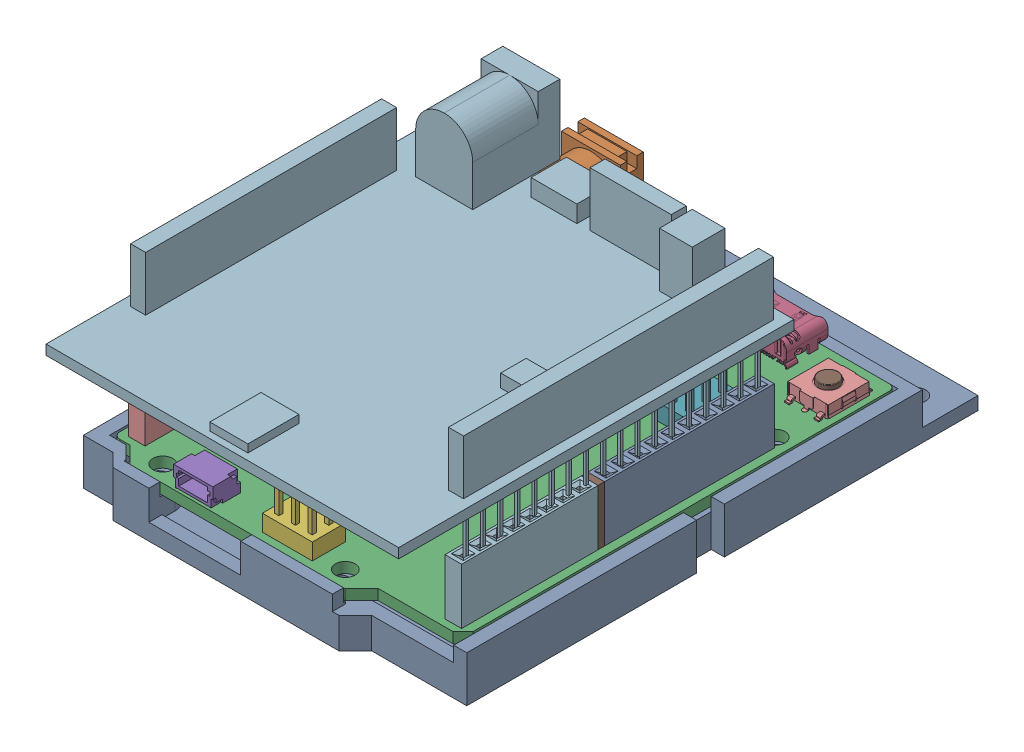
SolidWorks assembly Arduino_And_GPS_Module_C, configuration Default. Lengths in mm.
Overall size (59.4 35.6 86.3).
4 component instances, 3 part files, 4 mates.
Components (placement in the parent):
- Arduino_With_Mount_B-1: Arduino_With_Mount_B [Default] at origin size (59.4 17.89 80.5)
  - Arduino_Mount_B-2: Arduino_Mount_B [Default] at (0 2 0) x (-1 0 0) z (0 0 1) size (59.4 8 80.5)
  - Arduino_Uno_R4_Wifi_A-1: Arduino_Uno_R4_Wifi_A [Default] at (-26.67 7 -30.29) x (0 0 1) z (0 1 0) size (70.54 53.34 14.5)
- Pozyx-shield_A-1: Pozyx-shield_A [Default] at (0 22.5 15.6465) x (0 0 -1) z (1 0 0) size (63.6 25.6 53.8)
Mates (geometry in assembly coordinates):
- Parallel3: parallel anti-aligned: plane of Arduino_With_Mount_A-1/Arduino_Uno_R4_Wifi_A-1 through (-0.0974 7 3.3449) normal (0 1 0); plane of Pozyx-shield_A-1 through (0 22.5 15.6465) normal (0 -1 0)
- Width4: width anti-aligned: plane of Pozyx-shield_A-1 through (26.9 24 45.7965) normal (1 0 0); plane of Pozyx-shield_A-1 through (-26.9 24 45.7965) normal (-1 0 0); plane of Arduino_With_Mount_A-1/Arduino_Uno_R4_Wifi_A-1 through (-26.67 5.3937 34.75) normal (-1 0 0); plane of Arduino_With_Mount_A-1/Arduino_Uno_R4_Wifi_A-1 through (26.67 5.3937 -29.29) normal (1 0 0)
- Distance3: distance = 15.5 mm anti-aligned: plane of Arduino_With_Mount_A-1/Arduino_Mount_A-2 through (0 7 0) normal (0 1 0); plane of Pozyx-shield_A-1 through (0 22.5 15.6465) normal (0 -1 0)
- Distance4: distance = 17.4965 mm aligned: plane of Pozyx-shield_A-1 through (-26.9 24 -14.5035) normal (0 0 -1); plane of Arduino_With_Mount_A-1/Arduino_Mount_A-2 through (0 2.5 -32) normal (0 0 -1)
